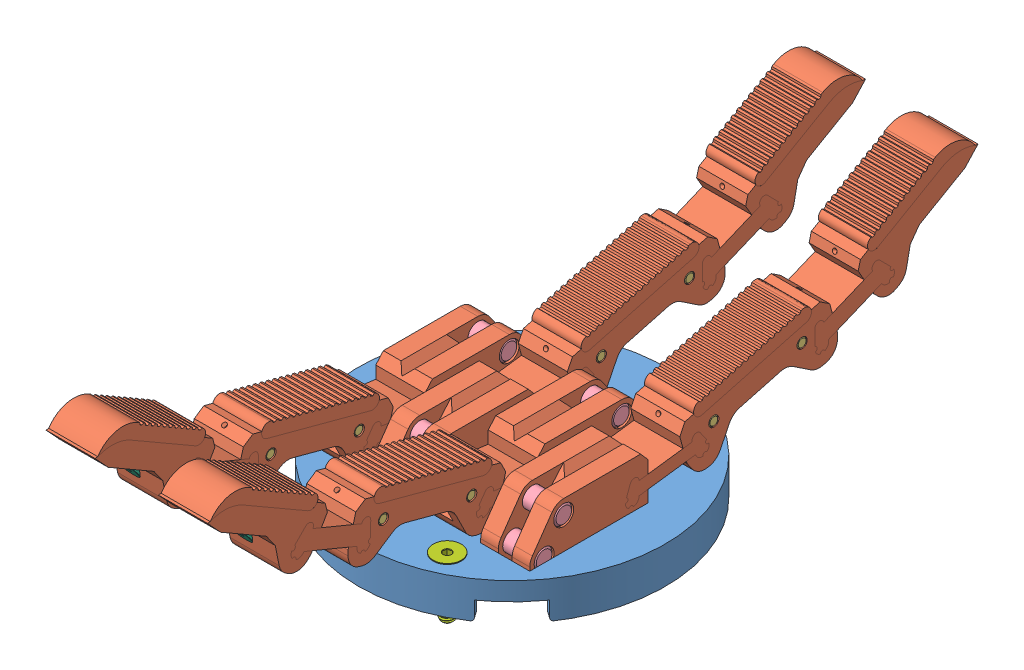
SolidWorks assembly block_top_ff_t, configuration Default. Lengths in mm.
Overall size (100 71.16 232.7).
37 component instances, 7 part files, 20 mates.
Components (placement in the parent):
- a1_f_t-1: a1_f_t [Default] at origin size (100 12.06 100)
- block_finger_ff_t-1: block_finger_ff_t [Default] at (-9.0917 8.2832 -0.0007) size (16 58.08 150.14)
  - finger_ff_t-1: finger_ff_t [Default] at origin size (16 58.08 150.14)
  - 98381A472 D1-8 L5-8-1: 98381A472 D1-8 L5-8 [98381A472] at (0.0625 5.5634 -30.2193) size (15.88 3.17 3.17)
  - 98381A472 D1-8 L5-8-2: 98381A472 D1-8 L5-8 [98381A472] at (0.0625 13.2775 -59.0086) size (15.88 3.17 3.17)
  - 98381A539 D1-4 L5-8-1: 98381A539 D1-4 L5-8 [98381A539] at (0.0625 3.5418 18.7031) size (15.88 6.35 6.35)
  - 98381A539 D1-4 L5-8-2: 98381A539 D1-4 L5-8 [98381A539] at (0.0625 -5.6082 25.11) size (15.88 6.35 6.35)
  - 93365A120 4-40 insert-1: 93365A120 4-40 insert [93365A120] at (0 25.5032 -95.7226) x (1 0 0) z (0 0.812659 -0.582739) size (4.37 3.82 4.37)
  - 91253A106 4-40 L1-4 countersunk-1: 91253A106 4-40 L1-4 countersunk [91253A106] at (0 24.2671 -97.4464) x (0.996599 0.066964 -0.048019) z (0 -0.582739 -0.812659) size (6.48 6.48 6.63)
- block_finger_ff_t-2: block_finger_ff_t [Default] at (27.575 8.2832 -0.0007) size (16 58.08 150.14)
  - finger_ff_t-1: finger_ff_t [Default] at origin size (16 58.08 150.14)
  - 98381A472 D1-8 L5-8-1: 98381A472 D1-8 L5-8 [98381A472] at (0.0625 5.5634 -30.2193) size (15.88 3.17 3.17)
  - 98381A472 D1-8 L5-8-2: 98381A472 D1-8 L5-8 [98381A472] at (0.0625 13.2775 -59.0086) size (15.88 3.17 3.17)
  - 98381A539 D1-4 L5-8-1: 98381A539 D1-4 L5-8 [98381A539] at (0.0625 3.5418 18.7031) size (15.88 6.35 6.35)
  - 98381A539 D1-4 L5-8-2: 98381A539 D1-4 L5-8 [98381A539] at (0.0625 -5.6082 25.11) size (15.88 6.35 6.35)
  - 93365A120 4-40 insert-1: 93365A120 4-40 insert [93365A120] at (0 25.5032 -95.7226) x (1 0 0) z (0 0.812659 -0.582739) size (4.37 3.82 4.37)
  - 91253A106 4-40 L1-4 countersunk-1: 91253A106 4-40 L1-4 countersunk [91253A106] at (0 24.2671 -97.4464) x (0.996599 0.066964 -0.048019) z (0 -0.582739 -0.812659) size (6.48 6.48 6.63)
- block_finger_ff_t-3: block_finger_ff_t [Default] at (-27.575 8.2832 0.0007) x (-1 0 0) z (0 0 -1) size (16 58.08 150.14)
  - finger_ff_t-1: finger_ff_t [Default] at origin size (16 58.08 150.14)
  - 98381A472 D1-8 L5-8-1: 98381A472 D1-8 L5-8 [98381A472] at (0.0625 5.5634 -30.2193) size (15.88 3.17 3.17)
  - 98381A472 D1-8 L5-8-2: 98381A472 D1-8 L5-8 [98381A472] at (0.0625 13.2775 -59.0086) size (15.88 3.17 3.17)
  - 98381A539 D1-4 L5-8-1: 98381A539 D1-4 L5-8 [98381A539] at (0.0625 3.5418 18.7031) size (15.88 6.35 6.35)
  - 98381A539 D1-4 L5-8-2: 98381A539 D1-4 L5-8 [98381A539] at (0.0625 -5.6082 25.11) size (15.88 6.35 6.35)
  - 93365A120 4-40 insert-1: 93365A120 4-40 insert [93365A120] at (0 25.5032 -95.7226) x (1 0 0) z (0 0.812659 -0.582739) size (4.37 3.82 4.37)
  - 91253A106 4-40 L1-4 countersunk-1: 91253A106 4-40 L1-4 countersunk [91253A106] at (0 24.2671 -97.4464) x (0.996599 0.066964 -0.048019) z (0 -0.582739 -0.812659) size (6.48 6.48 6.63)
- block_finger_ff_t-4: block_finger_ff_t [Default] at (9.0917 8.2832 0.0007) x (-1 0 0) z (0 0 -1) size (16 58.08 150.14)
  - finger_ff_t-1: finger_ff_t [Default] at origin size (16 58.08 150.14)
  - 98381A472 D1-8 L5-8-1: 98381A472 D1-8 L5-8 [98381A472] at (0.0625 5.5634 -30.2193) size (15.88 3.17 3.17)
  - 98381A472 D1-8 L5-8-2: 98381A472 D1-8 L5-8 [98381A472] at (0.0625 13.2775 -59.0086) size (15.88 3.17 3.17)
  - 98381A539 D1-4 L5-8-1: 98381A539 D1-4 L5-8 [98381A539] at (0.0625 3.5418 18.7031) size (15.88 6.35 6.35)
  - 98381A539 D1-4 L5-8-2: 98381A539 D1-4 L5-8 [98381A539] at (0.0625 -5.6082 25.11) size (15.88 6.35 6.35)
  - 93365A120 4-40 insert-1: 93365A120 4-40 insert [93365A120] at (0 25.5032 -95.7226) x (1 0 0) z (0 0.812659 -0.582739) size (4.37 3.82 4.37)
  - 91253A106 4-40 L1-4 countersunk-1: 91253A106 4-40 L1-4 countersunk [91253A106] at (0 24.2671 -97.4464) x (0.996599 0.066964 -0.048019) z (0 -0.582739 -0.812659) size (6.48 6.48 6.63)
- 92210A197 8-32 L3-4 countersunk-1: 92210A197 8-32 L3-4 countersunk [92210A197] at (17.0093 1.7845 38.128) x (-0.285144 0 -0.958485) z (0 1 0) size (9.12 9.12 19.5)
- 92210A197 8-32 L3-4 countersunk-2: 92210A197 8-32 L3-4 countersunk [92210A197] at (17.0093 1.7845 -38.128) x (1 0 0) z (0 1 0) size (9.12 9.12 19.5)
- 92210A197 8-32 L3-4 countersunk-3: 92210A197 8-32 L3-4 countersunk [92210A197] at (-17.0093 1.7845 38.128) x (1 0 0) z (0 1 0) size (9.12 9.12 19.5)
- 92210A197 8-32 L3-4 countersunk-4: 92210A197 8-32 L3-4 countersunk [92210A197] at (-17.0093 1.7845 -38.128) x (1 0 0) z (0 1 0) size (9.12 9.12 19.5)
Mates (geometry in assembly coordinates):
- Coincident1: coincident anti-aligned: plane of a1_f_t-1 through (-1.0917 1.5 29.7843) normal (-1 0 0); plane of block_finger_ff_t-1/finger_ff_t-1 through (-1.0917 8.2832 -0.0007) normal (1 0 0)
- Coincident2: coincident anti-aligned: plane of a1_f_t-1 through (-1.0917 1.5 29.7843) normal (0 0 -1); plane of block_finger_ff_t-1/finger_ff_t-1 through (-1.0917 16.5 29.7843) normal (0 0 1)
- Coincident3: coincident anti-aligned: plane of a1_f_t-1 through (0 -1.5 0) normal (0 -1 0); plane of block_finger_ff_t-1/finger_ff_t-1 through (-9.0917 -1.5 -0.0007) normal (0 1 0)
- Coincident4: coincident anti-aligned: plane of a1_f_t-1 through (35.575 1.5 29.7843) normal (-1 0 0); plane of block_finger_ff_t-2/finger_ff_t-1 through (35.575 8.2832 -0.0007) normal (1 0 0)
- Coincident5: coincident anti-aligned: plane of a1_f_t-1 through (0 -1.5 0) normal (0 -1 0); plane of block_finger_ff_t-2/finger_ff_t-1 through (27.575 -1.5 -0.0007) normal (0 1 0)
- Coincident6: coincident anti-aligned: plane of a1_f_t-1 through (35.575 1.5 29.7843) normal (0 0 -1); plane of block_finger_ff_t-2/finger_ff_t-1 through (35.575 16.5 29.7843) normal (0 0 1)
- Coincident7: coincident anti-aligned: plane of a1_f_t-1 through (1.0917 1.5 8.7858) normal (1 0 0); plane of block_finger_ff_t-4/finger_ff_t-1 through (1.0917 8.2832 0.0007) normal (-1 0 0)
- Coincident8: coincident anti-aligned: plane of a1_f_t-1 through (17.2417 1.5 -29.7843) normal (0 0 1); plane of block_finger_ff_t-4/finger_ff_t-1 through (1.0917 16.5 -29.7843) normal (0 0 -1)
- Coincident9: coincident anti-aligned: plane of a1_f_t-1 through (0 -1.5 0) normal (0 -1 0); plane of block_finger_ff_t-4/finger_ff_t-1 through (9.0917 -1.5 0.0007) normal (0 1 0)
- Coincident10: coincident anti-aligned: plane of a1_f_t-1 through (-35.575 1.5 8.7858) normal (1 0 0); plane of block_finger_ff_t-3/finger_ff_t-1 through (-35.575 8.2832 0.0007) normal (-1 0 0)
- Coincident11: coincident anti-aligned: plane of a1_f_t-1 through (-19.425 1.5 -29.7843) normal (0 0 1); plane of block_finger_ff_t-3/finger_ff_t-1 through (-35.575 16.5 -29.7843) normal (0 0 -1)
- Coincident12: coincident anti-aligned: plane of a1_f_t-1 through (0 -1.5 0) normal (0 -1 0); plane of block_finger_ff_t-3/finger_ff_t-1 through (-27.575 -1.5 0.0007) normal (0 1 0)
- Concentric1: concentric aligned: cylinder of a1_f_t-1 through (17.0093 1.5 38.128) axis (0 1 0) radius 2.2479; circle of 92210A197 8-32 L3-4 countersunk-1
- Coincident13: coincident aligned: cone of a1_f_t-1 through (17.0093 1.5 38.128) axis (0 -1 0); cone of 92210A197 8-32 L3-4 countersunk-1 through (17.0093 -1.0603 38.128) axis (0 -1 0)
- Concentric3: concentric aligned: cylinder of a1_f_t-1 through (17.0093 1.5 -38.128) axis (0 1 0) radius 2.2479; circle of 92210A197 8-32 L3-4 countersunk-2
- Coincident14: coincident aligned: cone of a1_f_t-1 through (17.0093 1.5 -38.128) axis (0 -1 0); cone of 92210A197 8-32 L3-4 countersunk-2 through (17.0093 -1.0603 -38.128) axis (0 -1 0)
- Concentric5: concentric aligned: cylinder of a1_f_t-1 through (-17.0093 1.5 -38.128) axis (0 1 0) radius 2.2479; circle of 92210A197 8-32 L3-4 countersunk-4
- Coincident15: coincident aligned: cone of a1_f_t-1 through (-17.0093 1.5 -38.128) axis (0 -1 0); cone of 92210A197 8-32 L3-4 countersunk-4 through (-17.0093 -1.0603 -38.128) axis (0 -1 0)
- Concentric7: concentric aligned: cylinder of a1_f_t-1 through (-17.0093 1.5 38.128) axis (0 1 0) radius 2.2479; circle of 92210A197 8-32 L3-4 countersunk-3
- Coincident16: coincident aligned: cone of a1_f_t-1 through (-17.0093 1.5 38.128) axis (0 -1 0); cone of 92210A197 8-32 L3-4 countersunk-3 through (-17.0093 -1.0603 38.128) axis (0 -1 0)
